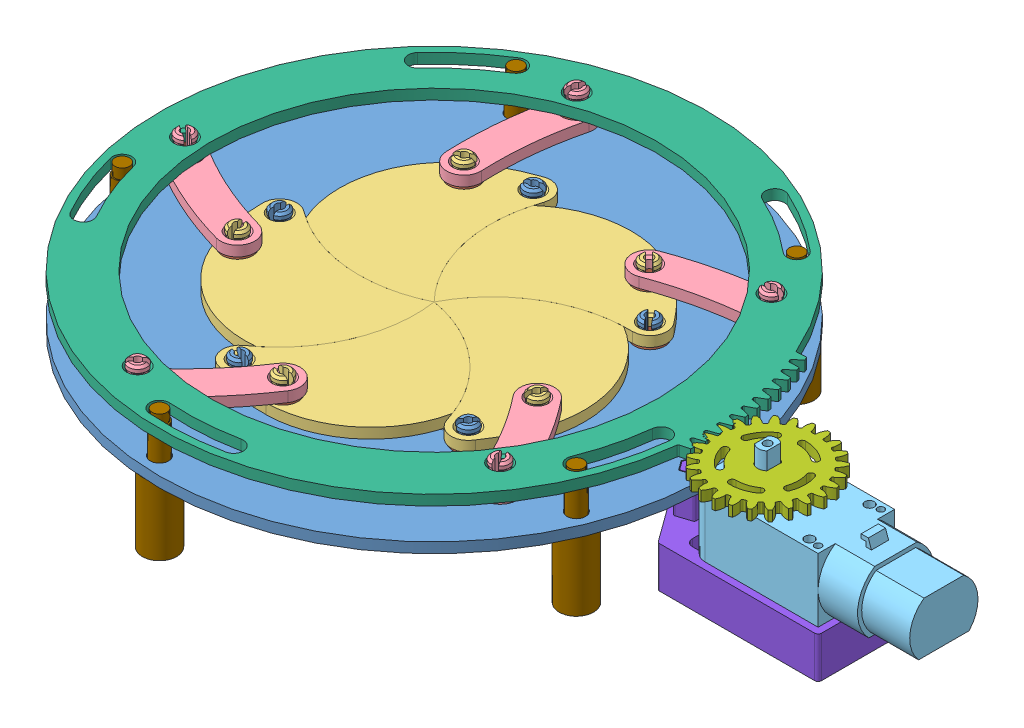
SolidWorks assembly full mechanism, configuration Default. Lengths in mm.
Overall size (247.06 39.9 197.8).
35 component instances, 9 part files, 77 mates.
Components (placement in the parent):
- backplate-1: backplate [Default] at (42.7202 76.2528 133.6504) size (160 8.65 160)
- washer-1: washer [Default] at (-2.2798 77.2528 133.6504) x (-0.837169 0 -0.546944) z (-0.546944 0 0.837169) size (8.75 1 8.75)
- washer-2: washer [Default] at (28.8144 77.2528 176.4479) x (-0.837169 0 -0.546944) z (-0.546944 0 0.837169) size (8.75 1 8.75)
- washer-3: washer [Default] at (79.1259 77.2528 160.1007) x (-0.837169 0 -0.546944) z (-0.546944 0 0.837169) size (8.75 1 8.75)
- washer-6: washer [Default] at (79.1259 77.2528 107.2001) x (-0.837169 0 -0.546944) z (-0.546944 0 0.837169) size (8.75 1 8.75)
- washer-7: washer [Default] at (28.8144 77.2528 90.8529) x (-0.837169 0 -0.546944) z (-0.546944 0 0.837169) size (8.75 1 8.75)
- shutter blade-1: shutter blade [Default] at (34.3546 80.2528 155.5704) x (-0.99492 0 -0.100673) z (0.100673 0 -0.99492) size (49.65 8.65 52.37)
- shutter blade-2: shutter blade [Default] at (60.9823 80.2528 148.3802) x (-0.403193 0 0.915115) z (-0.915115 0 -0.403193) size (49.65 8.65 52.37)
- shutter blade-3: shutter blade [Default] at (62.3724 80.2528 120.8339) x (0.745733 0 0.666245) z (-0.666245 0 0.745733) size (49.65 8.65 52.37)
- shutter blade-4: shutter blade [Default] at (36.6038 80.2528 110.9995) x (0.864081 0 -0.503353) z (0.503353 0 0.864081) size (49.65 8.65 52.37)
- shutter blade-5: shutter blade [Default] at (19.2879 80.2528 132.4679) x (-0.211701 0 -0.977334) z (0.977334 0 -0.211701) size (49.65 8.65 52.37)
- washer-8: washer [Default] at (85.7969 81.2528 146.6658) x (0.837169 0 0.546944) z (0.546944 0 -0.837169) size (8.75 1 8.75)
- washer-9: washer [Default] at (68.4099 81.2528 96.704) x (-0.837169 0 -0.546944) z (-0.546944 0 0.837169) size (8.75 1 8.75)
- washer-10: washer [Default] at (15.5206 81.2528 97.8009) x (-0.837169 0 -0.546944) z (-0.546944 0 0.837169) size (8.75 1 8.75)
- washer-11: washer [Default] at (0.2202 81.2528 148.4406) x (-0.837169 0 -0.546944) z (-0.546944 0 0.837169) size (8.75 1 8.75)
- washer-12: washer [Default] at (43.6533 81.2528 178.6407) x (-0.837169 0 -0.546944) z (-0.546944 0 0.837169) size (8.75 1 8.75)
- 30mm link-6: 30mm link [Default] at (15.5206 84.2528 97.8009) x (-0.101076 0 0.994879) z (-0.994879 0 -0.101076) size (40 8.65 11.08)
- 30mm link-7: 30mm link [Default] at (0.2202 84.2528 148.4406) x (0.914952 0 0.403563) z (-0.403563 0 0.914952) size (40 8.65 11.08)
- 30mm link-8: 30mm link [Default] at (43.6533 84.2528 178.6407) x (0.666547 0 -0.745463) z (0.745463 0 0.666547) size (40 8.65 11.08)
- 30mm link-9: 30mm link [Default] at (85.7969 84.2528 146.6658) x (-0.503003 0 -0.864285) z (0.864285 0 -0.503003) size (40 8.65 11.08)
- 30mm link-10: 30mm link [Default] at (68.4099 84.2528 96.704) x (-0.97742 0 0.211306) z (-0.211306 0 -0.97742) size (40 8.65 11.08)
- washer-13: washer [Default] at (23.6569 85.2528 201.0046) x (-0.837169 0 -0.546944) z (-0.546944 0 0.837169) size (8.75 1 8.75)
- washer-14: washer [Default] at (100.8869 85.2528 172.5943) x (-0.837169 0 -0.546944) z (-0.546944 0 0.837169) size (8.75 1 8.75)
- washer-15: washer [Default] at (97.7325 85.2528 90.3648) x (-0.837169 0 -0.546944) z (-0.546944 0 0.837169) size (8.75 1 8.75)
- washer-16: washer [Default] at (18.5529 85.2528 67.9546) x (-0.837169 0 -0.546944) z (-0.546944 0 0.837169) size (8.75 1 8.75)
- washer-17: washer [Default] at (-27.2284 85.2528 136.3337) x (-0.837169 0 -0.546944) z (-0.546944 0 0.837169) size (8.75 1 8.75)
- motor-1: motor [Default] at (128.7577 74.5528 133.6504) x (1 0 0) z (0 0 -1) size (67.5 37.2 22.3)
- ring-1: ring [Default] at (42.7202 88.2528 133.6504) x (0.963364 0 -0.268199) z (0.268199 0 0.963364) size (162.8 3 160)
- pinion-1: pinion [Default] at (139.9077 88.2528 133.6504) x (-0.016451 0 0.999865) z (-0.999865 0 -0.016451) size (33.72 3 33.69)
- motor mount 2-1: motor mount 2 [Default] at (139.9077 65.2528 133.6504) size (55.98 28 26.3)
- peg stand-1: peg stand [Default] at (112.259 53.2528 161.7459) size (10 35 10)
- peg stand-2: peg stand [Default] at (37.4884 53.2528 208.4677) size (10 35 10)
- peg stand-3: peg stand [Default] at (-30.052 53.2528 151.7945) size (10 35 10)
- peg stand-4: peg stand [Default] at (90.9292 53.2528 76.1971) size (10 35 10)
- peg stand-5: peg stand [Default] at (2.9762 53.2528 70.0468) size (10 35 10)
Mates (geometry in assembly coordinates):
- Coincident1: coincident anti-aligned: plane of backplate-1 through (42.7202 76.2528 133.6504) normal (0 1 0); plane of washer-1 through (-2.2798 76.2528 133.6504) normal (0 -1 0)
- Coincident2: coincident anti-aligned: plane of backplate-1 through (42.7202 76.2528 133.6504) normal (0 1 0); plane of washer-2 through (28.8144 76.2528 176.4479) normal (0 -1 0)
- Coincident4: coincident anti-aligned: plane of backplate-1 through (42.7202 76.2528 133.6504) normal (0 1 0); plane of washer-3 through (79.1259 76.2528 160.1007) normal (0 -1 0)
- Coincident5: coincident anti-aligned: plane of backplate-1 through (42.7202 76.2528 133.6504) normal (0 1 0); plane of washer-6 through (79.1259 76.2528 107.2001) normal (0 -1 0)
- Coincident6: coincident anti-aligned: plane of backplate-1 through (42.7202 76.2528 133.6504) normal (0 1 0); plane of washer-7 through (28.8144 76.2528 90.8529) normal (0 -1 0)
- Concentric1: concentric anti-aligned: cylinder of backplate-1 through (-2.2798 80.2528 133.6504) axis (0 -1 0) radius 2.3; cylinder of washer-1 through (-2.2798 76.2528 133.6504) axis (0 1 0) radius 2.5
- Concentric2: concentric anti-aligned: cylinder of washer-2 through (28.8144 76.2528 176.4479) axis (0 1 0) radius 2.5; cylinder of backplate-1 through (28.8144 80.2528 176.4479) axis (0 -1 0) radius 2.3
- Concentric3: concentric anti-aligned: cylinder of backplate-1 through (79.1259 80.2528 160.1007) axis (0 -1 0) radius 2.3; cylinder of washer-3 through (79.1259 76.2528 160.1007) axis (0 1 0) radius 2.5
- Concentric4: concentric anti-aligned: cylinder of backplate-1 through (79.1259 80.2528 107.2001) axis (0 -1 0) radius 2.3; cylinder of washer-6 through (79.1259 76.2528 107.2001) axis (0 1 0) radius 2.5
- Concentric5: concentric anti-aligned: cylinder of backplate-1 through (28.8144 80.2528 90.8529) axis (0 -1 0) radius 2.3; cylinder of washer-7 through (28.8144 76.2528 90.8529) axis (0 1 0) radius 2.5
- Coincident7: coincident anti-aligned: plane of washer-3 through (79.1259 77.2528 160.1007) normal (0 1 0); plane of shutter blade-1 through (34.3546 77.2528 155.5704) normal (0 -1 0)
- Coincident8: coincident anti-aligned: plane of washer-6 through (79.1259 77.2528 107.2001) normal (0 1 0); plane of shutter blade-2 through (60.9823 77.2528 148.3802) normal (0 -1 0)
- Coincident9: coincident anti-aligned: plane of washer-7 through (28.8144 77.2528 90.8529) normal (0 1 0); plane of shutter blade-3 through (62.3724 77.2528 120.8339) normal (0 -1 0)
- Coincident10: coincident anti-aligned: plane of washer-1 through (-2.2798 77.2528 133.6504) normal (0 1 0); plane of shutter blade-4 through (36.6038 77.2528 110.9995) normal (0 -1 0)
- Coincident11: coincident anti-aligned: plane of washer-2 through (28.8144 77.2528 176.4479) normal (0 1 0); plane of shutter blade-5 through (19.2879 77.2528 132.4679) normal (0 -1 0)
- Concentric6: concentric anti-aligned: cylinder of backplate-1 through (79.1259 80.2528 160.1007) axis (0 -1 0) radius 2.3; cylinder of shutter blade-1 through (79.1259 77.2528 160.1007) axis (0 1 0) radius 2.5
- Concentric7: concentric anti-aligned: cylinder of backplate-1 through (79.1259 80.2528 107.2001) axis (0 -1 0) radius 2.3; cylinder of shutter blade-2 through (79.1259 77.2528 107.2001) axis (0 1 0) radius 2.5
- Concentric8: concentric anti-aligned: cylinder of backplate-1 through (28.8144 80.2528 90.8529) axis (0 -1 0) radius 2.3; cylinder of shutter blade-3 through (28.8144 77.2528 90.8529) axis (0 1 0) radius 2.5
- Concentric9: concentric anti-aligned: cylinder of backplate-1 through (-2.2798 80.2528 133.6504) axis (0 -1 0) radius 2.3; cylinder of shutter blade-4 through (-2.2798 77.2528 133.6504) axis (0 1 0) radius 2.5
- Concentric10: concentric anti-aligned: cylinder of backplate-1 through (28.8144 80.2528 176.4479) axis (0 -1 0) radius 2.3; cylinder of shutter blade-5 through (28.8144 77.2528 176.4479) axis (0 1 0) radius 2.5
- Coincident12: coincident anti-aligned: plane of shutter blade-1 through (34.3546 80.2528 155.5704) normal (0 1 0); plane of washer-8 through (85.7969 80.2528 146.6658) normal (0 -1 0)
- Coincident13: coincident anti-aligned: plane of shutter blade-2 through (60.9823 80.2528 148.3802) normal (0 1 0); plane of washer-9 through (68.4099 80.2528 96.704) normal (0 -1 0)
- Coincident14: coincident anti-aligned: plane of shutter blade-3 through (62.3724 80.2528 120.8339) normal (0 1 0); plane of washer-10 through (15.5206 80.2528 97.8009) normal (0 -1 0)
- Coincident15: coincident anti-aligned: plane of shutter blade-4 through (36.6038 80.2528 110.9995) normal (0 1 0); plane of washer-11 through (0.2202 80.2528 148.4406) normal (0 -1 0)
- Coincident16: coincident anti-aligned: plane of shutter blade-5 through (19.2879 80.2528 132.4679) normal (0 1 0); plane of washer-12 through (43.6533 80.2528 178.6407) normal (0 -1 0)
- Parallel1: parallel aligned: plane of shutter blade-1 through (34.3546 80.2528 155.5704) normal (0 1 0); plane of washer-8 through (85.7969 81.2528 146.6658) normal (0 1 0)
- Concentric11: concentric anti-aligned: cylinder of shutter blade-1 through (85.7969 84.2528 146.6658) axis (0 -1 0) radius 2.3; cylinder of washer-8 through (85.7969 80.2528 146.6658) axis (0 1 0) radius 2.5
- Concentric12: concentric anti-aligned: cylinder of shutter blade-2 through (68.4099 84.2528 96.704) axis (0 -1 0) radius 2.3; cylinder of washer-9 through (68.4099 80.2528 96.704) axis (0 1 0) radius 2.5
- Concentric13: concentric anti-aligned: cylinder of shutter blade-3 through (15.5206 84.2528 97.8009) axis (0 -1 0) radius 2.3; cylinder of washer-10 through (15.5206 80.2528 97.8009) axis (0 1 0) radius 2.5
- Concentric14: concentric anti-aligned: cylinder of shutter blade-4 through (0.2202 84.2528 148.4406) axis (0 -1 0) radius 2.3; cylinder of washer-11 through (0.2202 80.2528 148.4406) axis (0 1 0) radius 2.5
- Concentric15: concentric anti-aligned: cylinder of shutter blade-5 through (43.6533 84.2528 178.6407) axis (0 -1 0) radius 2.3; cylinder of washer-12 through (43.6533 80.2528 178.6407) axis (0 1 0) radius 2.5
- Coincident18: coincident anti-aligned: plane of washer-9 through (68.4099 81.2528 96.704) normal (0 1 0); plane of 30mm link-10 through (68.4099 81.2528 96.704) normal (0 -1 0)
- Coincident19: coincident anti-aligned: plane of washer-10 through (15.5206 81.2528 97.8009) normal (0 1 0); plane of 30mm link-6 through (15.5206 81.2528 97.8009) normal (0 -1 0)
- Coincident20: coincident anti-aligned: plane of washer-11 through (0.2202 81.2528 148.4406) normal (0 1 0); plane of 30mm link-7 through (0.2202 81.2528 148.4406) normal (0 -1 0)
- Coincident21: coincident anti-aligned: plane of washer-12 through (43.6533 81.2528 178.6407) normal (0 1 0); plane of 30mm link-8 through (43.6533 81.2528 178.6407) normal (0 -1 0)
- Coincident22: coincident anti-aligned: plane of washer-8 through (85.7969 81.2528 146.6658) normal (0 1 0); plane of 30mm link-9 through (85.7969 81.2528 146.6658) normal (0 -1 0)
- Coincident23: coincident anti-aligned: plane of washer-9 through (68.4099 81.2528 96.704) normal (0 1 0); plane of 30mm link-10 through (68.4099 81.2528 96.704) normal (0 -1 0)
- Concentric16: concentric anti-aligned: cylinder of shutter blade-3 through (15.5206 84.2528 97.8009) axis (0 -1 0) radius 2.3; cylinder of 30mm link-6 through (15.5206 74.1818 97.8009) axis (0 1 0) radius 2.5
- Concentric17: concentric anti-aligned: cylinder of shutter blade-4 through (0.2202 84.2528 148.4406) axis (0 -1 0) radius 2.3; cylinder of 30mm link-7 through (0.2202 74.1818 148.4406) axis (0 1 0) radius 2.5
- Concentric18: concentric anti-aligned: cylinder of shutter blade-5 through (43.6533 84.2528 178.6407) axis (0 -1 0) radius 2.3; cylinder of 30mm link-8 through (43.6533 74.1818 178.6407) axis (0 1 0) radius 2.5
- Concentric19: concentric anti-aligned: cylinder of shutter blade-1 through (85.7969 84.2528 146.6658) axis (0 -1 0) radius 2.3; cylinder of 30mm link-9 through (85.7969 74.1818 146.6658) axis (0 1 0) radius 2.5
- Concentric20: concentric anti-aligned: cylinder of shutter blade-2 through (68.4099 84.2528 96.704) axis (0 -1 0) radius 2.3; cylinder of 30mm link-10 through (68.4099 74.1818 96.704) axis (0 1 0) radius 2.5
- Coincident24: coincident anti-aligned: plane of 30mm link-8 through (43.6533 84.2528 178.6407) normal (0 1 0); plane of washer-13 through (23.6569 84.2528 201.0046) normal (0 -1 0)
- Coincident25: coincident anti-aligned: plane of 30mm link-9 through (85.7969 84.2528 146.6658) normal (0 1 0); plane of washer-14 through (100.8869 84.2528 172.5943) normal (0 -1 0)
- Coincident26: coincident anti-aligned: plane of 30mm link-10 through (68.4099 84.2528 96.704) normal (0 1 0); plane of washer-15 through (97.7325 84.2528 90.3648) normal (0 -1 0)
- Coincident27: coincident anti-aligned: plane of 30mm link-6 through (15.5206 84.2528 97.8009) normal (0 1 0); plane of washer-16 through (18.5529 84.2528 67.9546) normal (0 -1 0)
- Coincident28: coincident anti-aligned: plane of 30mm link-7 through (0.2202 84.2528 148.4406) normal (0 1 0); plane of washer-17 through (-27.2284 84.2528 136.3337) normal (0 -1 0)
- Concentric21: concentric anti-aligned: cylinder of 30mm link-8 through (23.6569 88.2528 201.0046) axis (0 -1 0) radius 2.3; cylinder of washer-13 through (23.6569 84.2528 201.0046) axis (0 1 0) radius 2.5
- Concentric22: concentric anti-aligned: cylinder of 30mm link-9 through (100.8869 88.2528 172.5943) axis (0 -1 0) radius 2.3; cylinder of washer-14 through (100.8869 84.2528 172.5943) axis (0 1 0) radius 2.5
- Concentric23: concentric anti-aligned: cylinder of 30mm link-10 through (97.7325 88.2528 90.3648) axis (0 -1 0) radius 2.3; cylinder of washer-15 through (97.7325 84.2528 90.3648) axis (0 1 0) radius 2.5
- Concentric24: concentric anti-aligned: cylinder of 30mm link-6 through (18.5529 88.2528 67.9546) axis (0 -1 0) radius 2.3; cylinder of washer-16 through (18.5529 84.2528 67.9546) axis (0 1 0) radius 2.5
- Concentric25: concentric anti-aligned: cylinder of 30mm link-7 through (-27.2284 88.2528 136.3337) axis (0 -1 0) radius 2.3; cylinder of washer-17 through (-27.2284 84.2528 136.3337) axis (0 1 0) radius 2.5
- Distance1: distance = 9 mm anti-aligned: plane of ring-1 through (42.7202 85.2528 133.6504) normal (0 -1 0); plane of backplate-1 through (42.7202 76.2528 133.6504) normal (0 1 0)
- Concentric26: concentric aligned: cylinder of backplate-1 through (42.7202 73.2528 133.6504) axis (0 1 0) radius 40; cylinder of ring-1 through (42.7202 85.2528 133.6504) axis (0 1 0) radius 65
- Concentric27: concentric anti-aligned: cylinder of 30mm link-8 through (23.6569 88.2528 201.0046) axis (0 -1 0) radius 2.3; cylinder of ring-1 through (23.6569 85.2528 201.0046) axis (0 1 0) radius 2.5
- Concentric28: concentric anti-aligned: cylinder of 30mm link-9 through (100.8869 88.2528 172.5943) axis (0 -1 0) radius 2.3; cylinder of ring-1 through (100.8869 85.2528 172.5943) axis (0 1 0) radius 2.5
- Concentric29: concentric anti-aligned: cylinder of 30mm link-10 through (97.7325 88.2528 90.3648) axis (0 -1 0) radius 2.3; cylinder of ring-1 through (97.7325 85.2528 90.3648) axis (0 1 0) radius 2.5
- Concentric30: concentric anti-aligned: cylinder of 30mm link-6 through (18.5529 88.2528 67.9546) axis (0 -1 0) radius 2.3; cylinder of ring-1 through (18.5529 85.2528 67.9546) axis (0 1 0) radius 2.5
- Concentric31: concentric anti-aligned: cylinder of 30mm link-7 through (-27.2284 88.2528 136.3337) axis (0 -1 0) radius 2.3; cylinder of ring-1 through (-27.2284 85.2528 136.3337) axis (0 1 0) radius 2.5
- Coincident34: coincident anti-aligned: plane of motor-1 through (128.7577 85.2528 133.6504) normal (0 1 0); plane of pinion-1 through (139.9077 85.2528 133.6504) normal (0 -1 0)
- Concentric34: concentric anti-aligned: cylinder of motor-1 through (139.9077 93.1528 133.6504) axis (0 -1 0) radius 2.7; cylinder of pinion-1 through (139.9077 85.2528 133.6504) axis (0 1 0) radius 2.9
- Coincident36: coincident aligned: plane of ring-1 through (42.7202 88.2528 133.6504) normal (0 1 0); plane of pinion-1 through (139.9077 88.2528 133.6504) normal (0 1 0)
- Coincident37: coincident anti-aligned: plane of motor-1 through (165.7577 65.2528 122.5004) normal (0 -1 0); plane of motor mount 2-1 through (139.9077 65.2528 133.6504) normal (0 1 0)
- Concentric35: concentric aligned: cylinder of motor-1 through (139.9077 55.9528 133.6504) axis (0 1 0) radius 2.7; cylinder of motor mount 2-1 through (139.9077 53.2528 133.6504) axis (0 1 0) radius 5
- Concentric39: concentric aligned: cylinder of motor-1 through (160.8577 83.8528 142.4004) axis (0 -1 0) radius 1.4; cylinder of motor mount 2-1 through (160.8577 81.2528 142.4004) axis (0 -1 0) radius 1.25
- Distance2: distance = 0.2 mm anti-aligned: plane of motor mount 2-1 through (116.8695 73.2528 131.0323) normal (-0.809017 0 -0.587785); plane of backplate-1 through (116.7931 73.2528 130.7972) normal (0.809017 0 0.587785)
- Distance3: distance = 0.2 mm anti-aligned: plane of motor mount 2-1 through (114.9674 73.2528 133.6504) normal (-0.809017 0 0.587785); plane of backplate-1 through (114.7202 73.2528 133.6504) normal (0.809017 0 -0.587785)
- Concentric40: concentric anti-aligned: cylinder of backplate-1 through (112.259 73.2528 161.7459) axis (0 1 0) radius 2.7; cylinder of peg stand-1 through (112.259 85.2528 161.7459) axis (0 -1 0) radius 2.5
- Concentric41: concentric anti-aligned: cylinder of backplate-1 through (37.4884 73.2528 208.4677) axis (0 1 0) radius 2.7; cylinder of peg stand-2 through (37.4884 85.2528 208.4677) axis (0 -1 0) radius 2.5
- Concentric42: concentric anti-aligned: cylinder of backplate-1 through (-30.052 73.2528 151.7945) axis (0 1 0) radius 2.7; cylinder of peg stand-3 through (-30.052 85.2528 151.7945) axis (0 -1 0) radius 2.5
- Concentric43: concentric anti-aligned: cylinder of backplate-1 through (90.9292 73.2528 76.1971) axis (0 1 0) radius 2.7; cylinder of peg stand-4 through (90.9292 85.2528 76.1971) axis (0 -1 0) radius 2.5
- Concentric44: concentric anti-aligned: cylinder of backplate-1 through (2.9762 73.2528 70.0468) axis (0 1 0) radius 2.7; cylinder of peg stand-5 through (2.9762 85.2528 70.0468) axis (0 -1 0) radius 2.5
- Coincident38: coincident aligned: plane of ring-1 through (42.7202 88.2528 133.6504) normal (0 1 0); plane of peg stand-2 through (37.4884 88.2528 208.4677) normal (0 1 0)
- Coincident39: coincident aligned: plane of ring-1 through (42.7202 88.2528 133.6504) normal (0 1 0); plane of peg stand-1 through (112.259 88.2528 161.7459) normal (0 1 0)
- Coincident40: coincident aligned: plane of ring-1 through (42.7202 88.2528 133.6504) normal (0 1 0); plane of peg stand-4 through (90.9292 88.2528 76.1971) normal (0 1 0)
- Coincident41: coincident aligned: plane of ring-1 through (42.7202 88.2528 133.6504) normal (0 1 0); plane of peg stand-5 through (2.9762 88.2528 70.0468) normal (0 1 0)
- Coincident42: coincident aligned: plane of ring-1 through (42.7202 88.2528 133.6504) normal (0 1 0); plane of peg stand-3 through (-30.052 88.2528 151.7945) normal (0 1 0)
